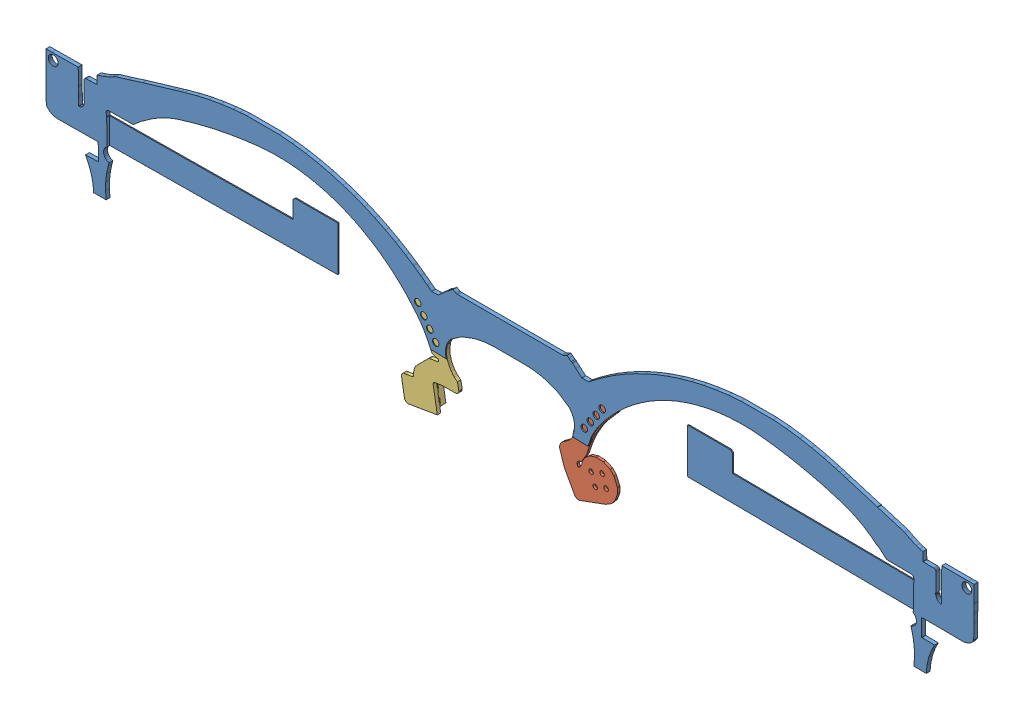
SolidWorks assembly flex_v2_outline, configuration Default. Lengths in mm.
Overall size (142.01 25.92 2.47).
3 component instances, 3 part files, 2 mates.
Components (placement in the parent):
- front_flex-1: front_flex [Default] at (45.2745 57.06 117.1341) size (142.01 21.92 0.59)
- nose_thermo-1: nose_thermo [Default] at (45.3253 57.2358 116.9595) size (8.88 16.32 0.41)
- nose_blink-1: nose_blink [Default] at (45.2573 57.0244 117.0595) size (8.78 15.62 2.37)
Mates (geometry in assembly coordinates):
- Distance1: distance = 0.1 mm aligned: plane of front_flex-1 through (107.0425 75.296 117.1595) normal (0 0 1); plane of nose_blink-1 through (35.5683 71.0254 117.0595) normal (0 0 1)
- Distance2: distance = 0.2 mm aligned: plane of front_flex-1 through (107.0425 75.296 117.1595) normal (0 0 1); plane of nose_thermo-1 through (53.4093 63.6218 116.9595) normal (0 0 1)
